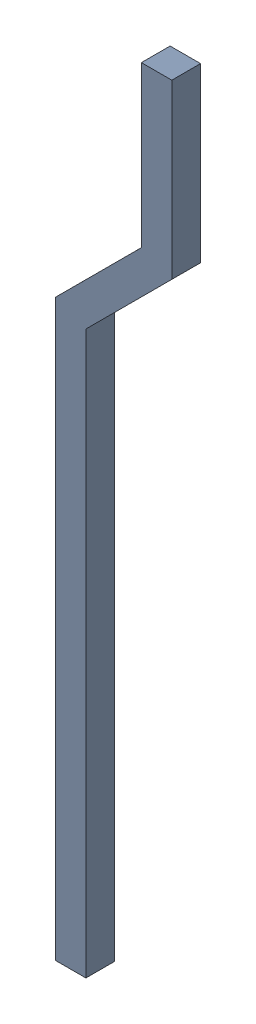
SolidWorks assembly Free-Models-1.step, configuration Default. Lengths in mm.
Overall size (1.81 12.71 0.46).
2 component instances, 1 part files, 0 mates.
Components (placement in the parent):
- 523779104.step-1: 523779104.step [Default] at (-0.665 -6.35 -0.35) size (1.81 12.71 0.46)
  - Extruded-43.step-1: Extruded-43.step [Default] at origin size (1.81 12.71 0.46)
